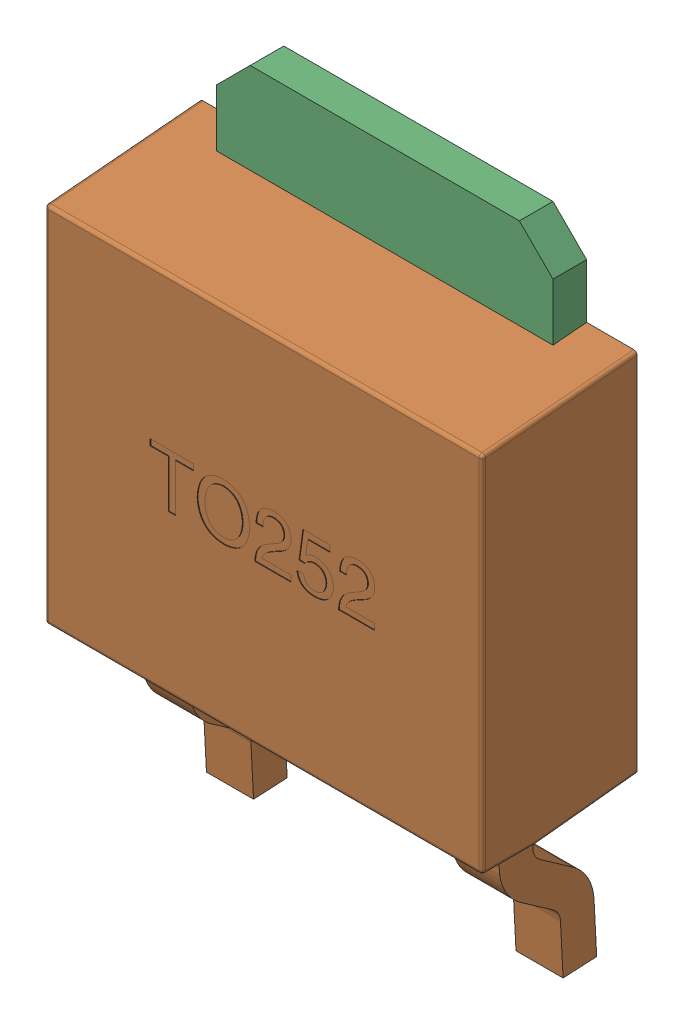
SolidWorks assembly TO252, configuration 默认. Lengths in mm.
Overall size (6.5 9.42 2.31).
2 component instances, 2 part files, 0 mates.
Components (placement in the parent):
- LOGO_-1: LOGO_ [默认] at (2.3503 3.4211 -0.0025) x (-1 0 0) z (0 0 -1) size (0.75 0.87 0.01)
- TO252-1: TO252 [默认] at origin size (6.5 9.42 2.3)
